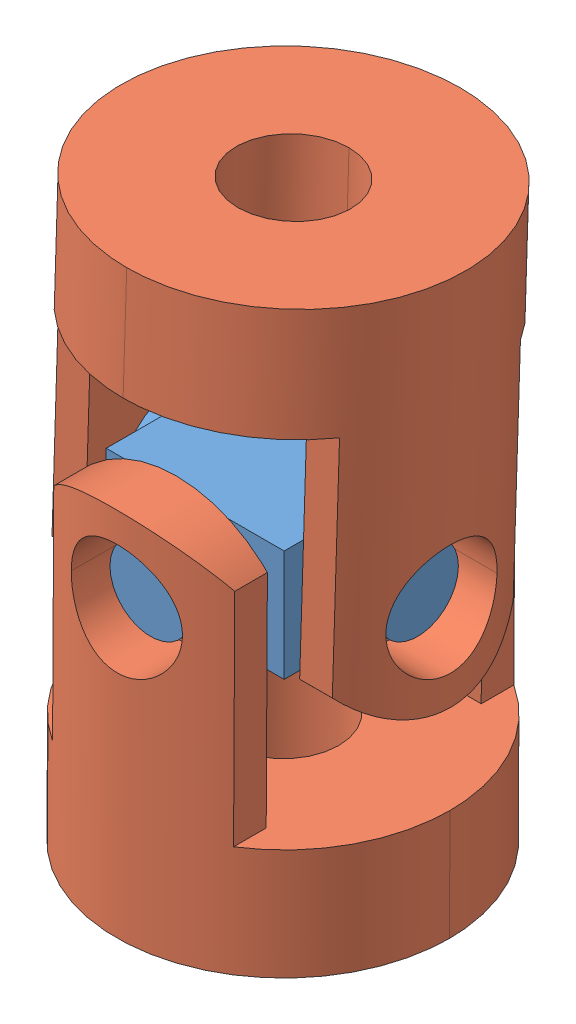
SolidWorks assembly UV_Final, configuration Default. Lengths in mm.
Overall size (9.05 15.57 9.32).
3 component instances, 2 part files, 4 mates.
Components (placement in the parent):
- UV cross spider[1].step-1: UV cross spider[1].step [Default] at (1.7499 4.175 5.7377) size (7.2 3 7.2)
- UV Yoke[1].step-1: UV Yoke[1].step [Default] at (1.7499 11.8709 5.4867) x (1 0 0) z (0 -0.032589 -0.999469) size (9.01 10 9)
- UV Yoke[1].step-2: UV Yoke[1].step [Default] at (1.7085 -3.5249 5.7377) x (0 0 -1) z (0.999986 -0.005381 0) size (9.01 10 9)
Mates (geometry in assembly coordinates):
- Concentric1: concentric aligned: cylinder of UV cross spider[1].step-1 through (5.3499 4.175 5.7377) axis (-1 0 0) radius 1.1; cylinder of UV Yoke[1].step-1 through (11.1499 4.175 5.7377) axis (-1 0 0) radius 1.5
- Width1: width aligned: plane of UV Yoke[1].step-1 through (-1.1501 1.8762 5.8126) normal (1 0 0); plane of UV cross spider[1].step-1 through (4.6499 1.8762 5.8126) normal (-1 0 0); plane of UV Yoke[1].step-1 through (4.1499 5.675 5.7377) normal (1 0 0); plane of UV cross spider[1].step-1 through (-0.6501 5.675 5.7377) normal (-1 0 0)
- Concentric2: concentric anti-aligned: cylinder of UV cross spider[1].step-1 through (1.7499 4.175 9.3377) axis (0 0 -1) radius 1.1; cylinder of UV Yoke[1].step-2 through (1.7499 4.175 -3.6623) axis (0 0 1) radius 1.5
- Width2: width anti-aligned: plane of UV Yoke[1].step-2 through (1.7623 6.475 2.8377) normal (0 0 1); plane of UV cross spider[1].step-1 through (1.7623 6.475 8.6377) normal (0 0 -1); plane of UV Yoke[1].step-2 through (1.7499 5.675 3.3377) normal (0 0 -1); plane of UV cross spider[1].step-1 through (1.7499 5.675 8.1377) normal (0 0 1)
